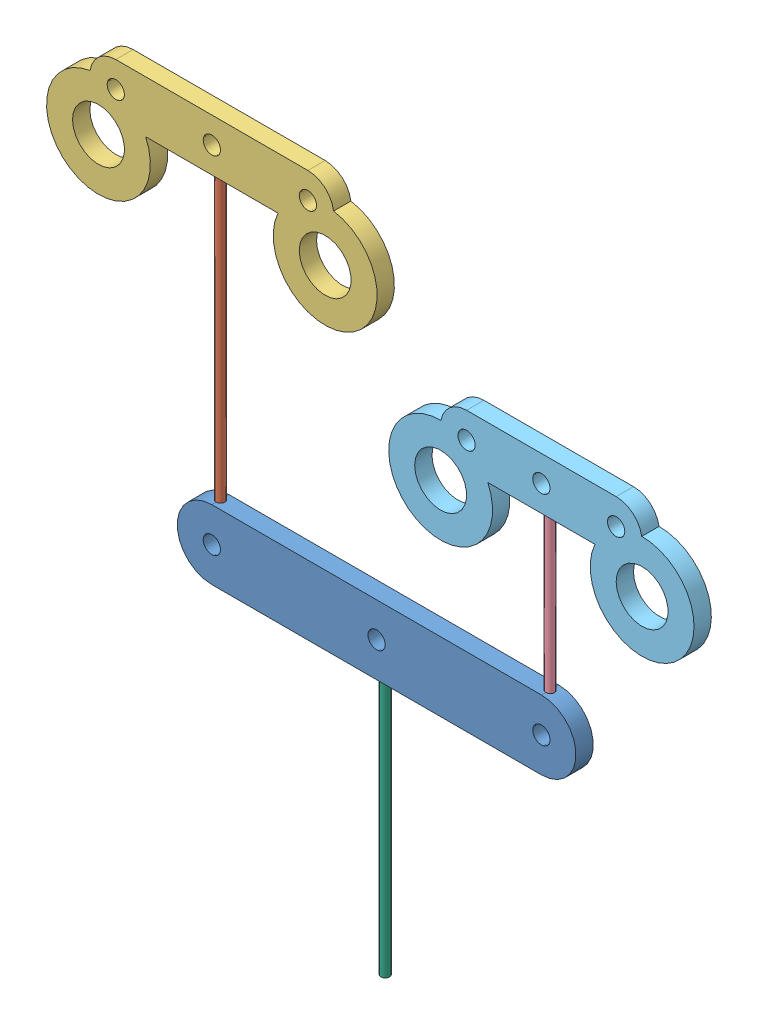
SolidWorks assembly whiffleetree, configuration Default. Lengths in mm.
Overall size (74.83 77 2).
6 component instances, 6 part files, 12 mates.
Components (placement in the parent):
- mainBar-1: mainBar [Default] at (20.3524 18.4625 38.0201) size (46.08 8 2)
- dynema1-1: dynema1 [Default] at (1.3104 55.9625 39.0201) x (0.250397 0 -0.968143) z (0 -1 0) size (1 1 34)
- barIndexMiddle-1: barIndexMiddle [Default] at (1.3104 58.4625 38.0201) size (38.2 14.5 2)
- dynema2-1: dynema2 [Default] at (39.3944 21.9625 39.0201) x (0.365635 0 0.930758) z (0 1 0) size (1 1 19.17)
- barMiddlePinky-1: barMiddlePinky [Default] at (39.3944 43.6325 38.0201) size (35.28 14.5 2)
- dynema3-1: dynema3 [Default] at (20.3524 14.9625 39.0201) x (0.922872 0 -0.385106) z (0 -1 0) size (1 1 30.5)
Mates (geometry in assembly coordinates):
- Concentric1: concentric aligned: cylinder of mainBar-1 through (1.3104 21.9625 39.0201) axis (0 1 0) radius 0.5; cylinder of dynema1-1 through (1.3104 21.9625 39.0201) axis (0 1 0) radius 0.5
- Coincident1: coincident anti-aligned: circle of mainBar-1; circle of dynema1-1
- Concentric2: concentric anti-aligned: cylinder of dynema1-1 through (1.3104 21.9625 39.0201) axis (0 1 0) radius 0.5; cylinder of barIndexMiddle-1 through (1.3104 55.9625 39.0201) axis (0 -1 0) radius 0.5
- Coincident2: coincident aligned: plane of mainBar-1 through (1.3104 18.4625 40.0201) normal (0 0 1); plane of barIndexMiddle-1 through (12.4106 58.4625 40.0201) normal (0 0 1)
- Coincident3: coincident aligned: circle of dynema1-1; plane of barIndexMiddle-1 through (1.3104 55.9625 39.0201) normal (0 -1 0)
- Concentric3: concentric anti-aligned: cylinder of mainBar-1 through (39.3944 21.9625 39.0201) axis (0 1 0) radius 0.5; cylinder of dynema2-1 through (39.3944 41.1325 39.0201) axis (0 -1 0) radius 0.5
- Coincident4: coincident aligned: circle of mainBar-1; circle of dynema2-1
- Concentric4: concentric aligned: cylinder of dynema2-1 through (39.3944 41.1325 39.0201) axis (0 -1 0) radius 0.5; cylinder of barMiddlePinky-1 through (39.3944 41.1325 39.0201) axis (0 -1 0) radius 0.5
- Coincident5: coincident aligned: plane of mainBar-1 through (1.3104 18.4625 40.0201) normal (0 0 1); plane of barMiddlePinky-1 through (27.7522 38.1325 40.0201) normal (0 0 1)
- Coincident6: coincident anti-aligned: circle of dynema2-1; circle of barMiddlePinky-1
- Concentric5: concentric anti-aligned: cylinder of mainBar-1 through (20.3524 14.9625 39.0201) axis (0 -1 0) radius 0.5; cylinder of dynema3-1 through (20.3524 -15.5375 39.0201) axis (0 1 0) radius 0.5
- Coincident7: coincident aligned: circle of mainBar-1; circle of dynema3-1
